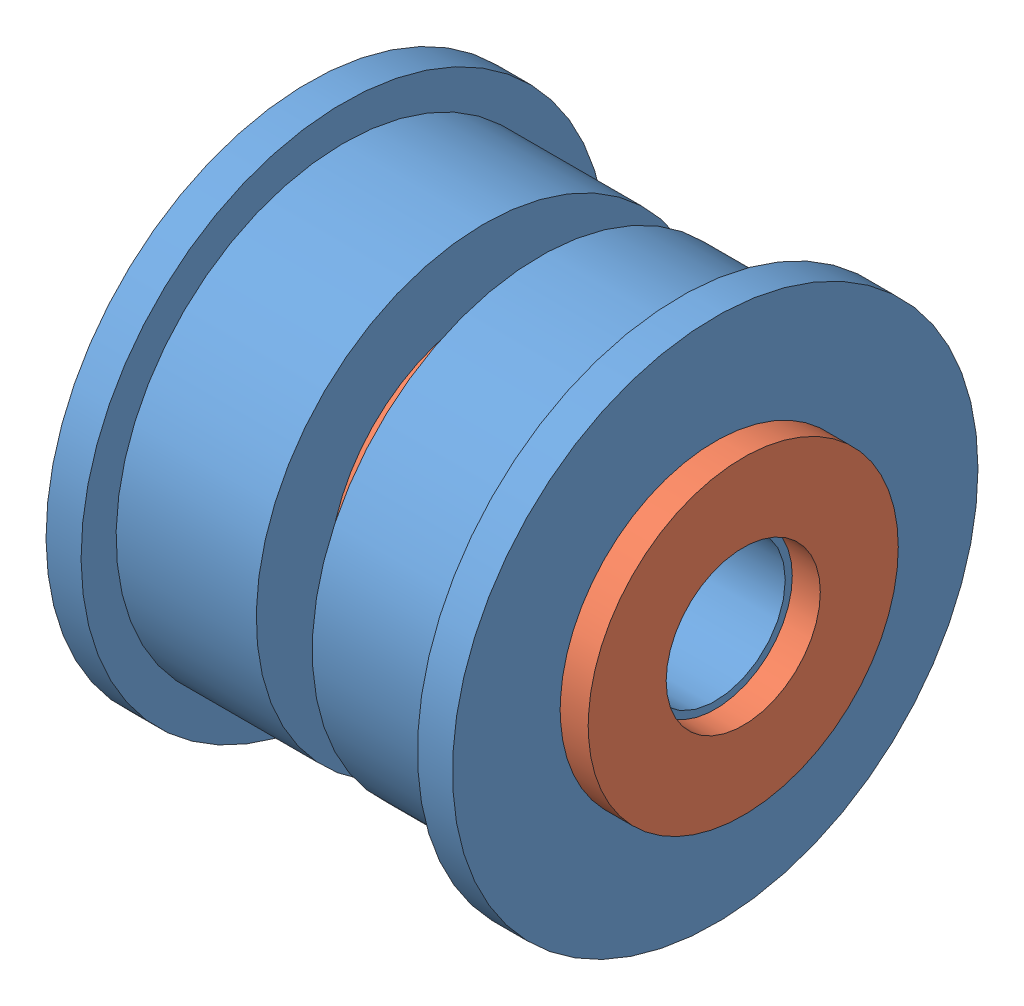
SolidWorks assembly Idler Assembly, configuration Default. Lengths in mm.
Overall size (13.2 19.59 19.59).
6 component instances, 2 part files, 10 mates.
Components (placement in the parent):
- F624ZZ-1: F624ZZ [Default] at (7.719 9.6467 10.7874) size (5 15 15)
- M4 Washer-1: M4 Washer [Default] at (1.3338 9.6467 10.7874) x (0 -1 0) z (0 0 1) size (8.85 0.8 8.85)
- M4 Washer-2: M4 Washer [Default] at (0.5338 9.6467 10.7874) x (0 -1 0) z (0 0 1) size (8.85 0.8 8.85)
- F624ZZ-3: F624ZZ [Default] at (-5.0514 9.6467 10.7874) x (-1 0 0) z (0 -0.924225 -0.381849) size (5 15 15)
- M4 Washer-3: M4 Washer [Default] at (-5.2662 9.6467 10.7874) x (0 -1 0) z (0 0 1) size (8.85 0.8 8.85)
- M4 Washer-4: M4 Washer [Default] at (7.1338 9.6467 10.7874) x (0 -1 0) z (0 0 1) size (8.85 0.8 8.85)
Mates (geometry in assembly coordinates):
- Coincident1: coincident anti-aligned: plane of F624ZZ-1 through (2.1338 16.1467 10.7874) normal (-1 0 0); plane of M4 Washer-1 through (2.1338 9.6467 10.7874) normal (1 0 0)
- Concentric1: concentric anti-aligned: cylinder of F624ZZ-1 through (7.719 9.6467 10.7874) axis (1 0 0) radius 2; cylinder of M4 Washer-1 through (2.1338 9.6467 10.7874) axis (-1 0 0) radius 4.425
- Coincident3: coincident anti-aligned: plane of M4 Washer-1 through (1.3338 9.6467 10.7874) normal (-1 0 0); plane of M4 Washer-2 through (1.3338 9.6467 10.7874) normal (1 0 0)
- Concentric3: concentric anti-aligned: cylinder of M4 Washer-1 through (2.1338 9.6467 10.7874) axis (-1 0 0) radius 2.2; circle of M4 Washer-2
- Concentric4: concentric aligned: cylinder of M4 Washer-2 through (1.3338 9.6467 10.7874) axis (-1 0 0) radius 2.2; cylinder of F624ZZ-3 through (-5.0514 9.6467 10.7874) axis (-1 0 0) radius 2
- Coincident4: coincident aligned: plane of M4 Washer-2 through (0.5338 9.6467 10.7874) normal (-1 0 0); circle of F624ZZ-3
- Coincident5: coincident anti-aligned: plane of F624ZZ-3 through (-4.4662 10.4104 8.939) normal (-1 0 0); plane of M4 Washer-3 through (-4.4662 9.6467 10.7874) normal (1 0 0)
- Concentric5: concentric anti-aligned: cylinder of F624ZZ-3 through (-5.0514 9.6467 10.7874) axis (-1 0 0) radius 2; circle of M4 Washer-3
- Coincident6: coincident aligned: plane of F624ZZ-1 through (7.1338 11.6467 10.7874) normal (1 0 0); circle of M4 Washer-4
- Concentric6: concentric anti-aligned: cylinder of F624ZZ-1 through (7.719 9.6467 10.7874) axis (1 0 0) radius 2; cylinder of M4 Washer-4 through (7.9338 9.6467 10.7874) axis (-1 0 0) radius 2.2
